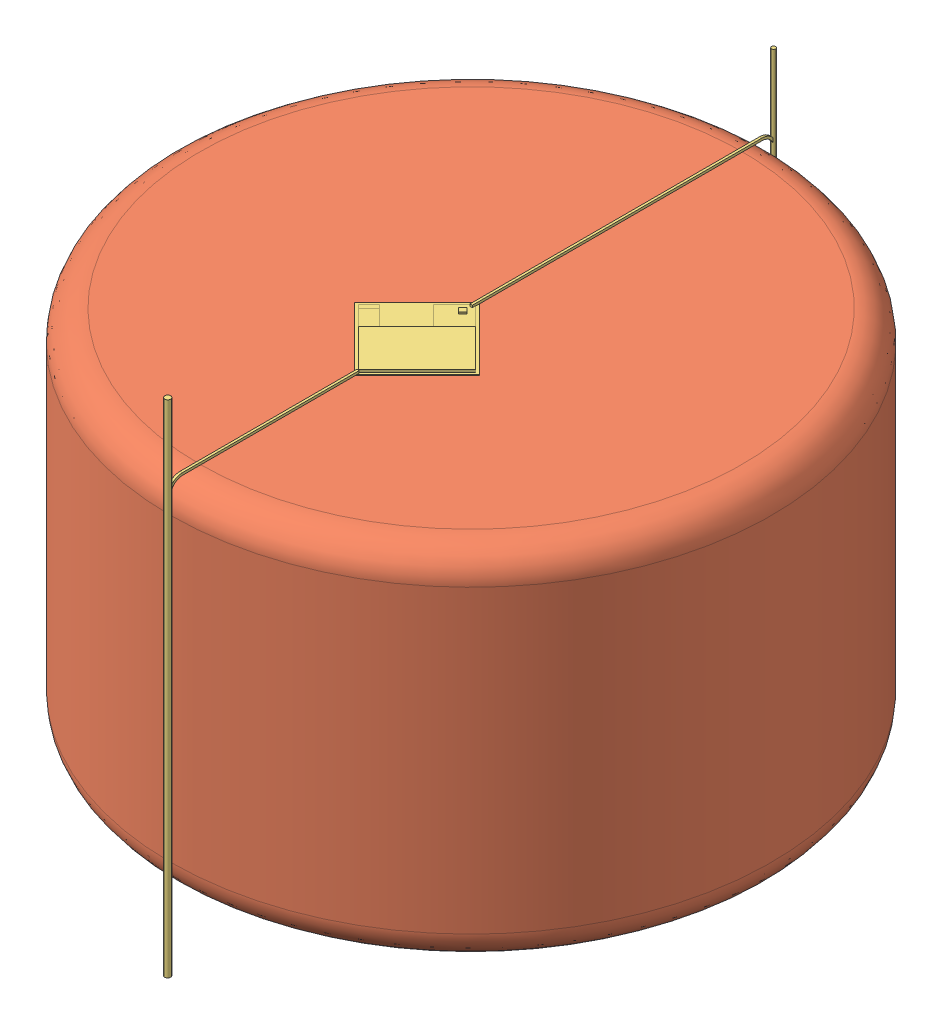
SolidWorks assembly 装配体1, configuration 默认. Lengths in mm.
Overall size (102 85 103.7).
3 component instances, 3 part files, 4 mates.
Components (placement in the parent):
- BEGeDet-2: BEGeDet [默认] at (1.9481 14.6195 80) x (1 0 0) z (0 0 -1) size (80 40 80)
- InnerShell-3: InnerShell [默认] at (1.9481 -36.3805 80) size (102 61 102)
- Electronics-1: Electronics [默认] at (1.9481 24.7195 80) x (-1 0 0) z (0 0 1) size (21.21 85 103.7)
Mates (geometry in assembly coordinates):
- 重合3: coincident anti-aligned: plane of BEGeDet-2 through (1.9481 14.6195 80) normal (0 1 0); plane of InnerShell-3 through (1.9481 14.6195 80) normal (0 -1 0)
- 同心1: concentric aligned: circle of BEGeDet-2; circle of InnerShell-3
- 重合5: coincident anti-aligned: plane of InnerShell-3 through (1.9481 24.6195 80) normal (0 1 0); plane of Electronics-1 through (1.9481 24.6195 99.799) normal (0 -1 0)
- 同心2: concentric anti-aligned: circle of InnerShell-3; circle of Electronics-1
